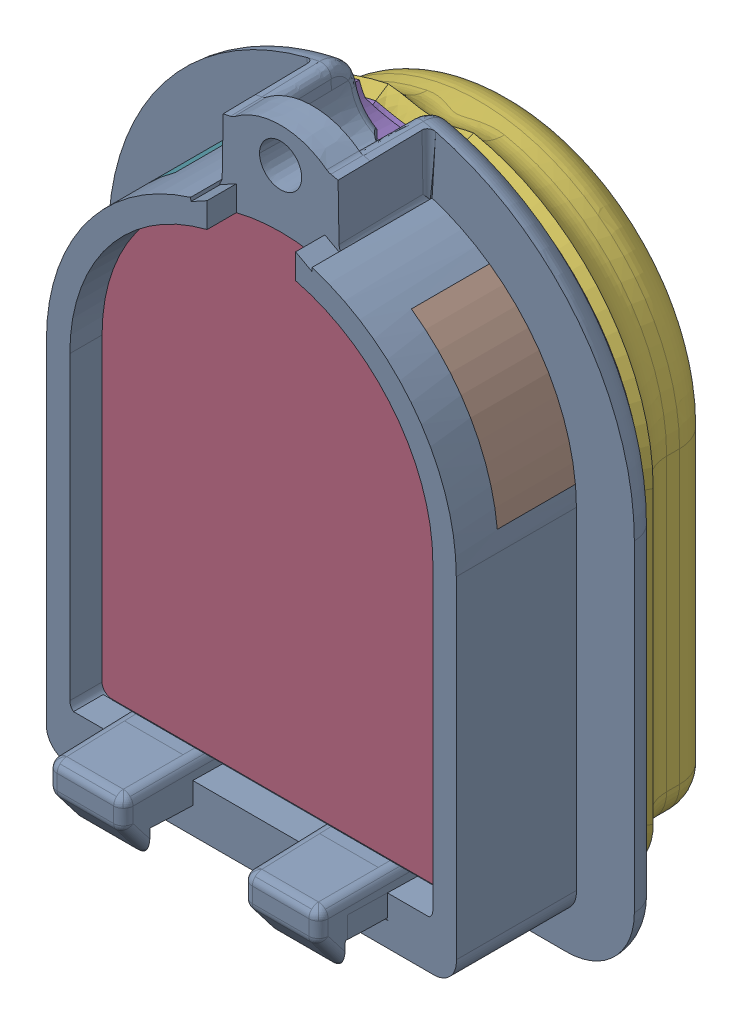
SolidWorks assembly PinDesign_2, configuration 默认. Lengths in mm.
Overall size (26.95 34.26 16.36).
9 component instances, 8 part files, 24 mates.
Components (placement in the parent):
- pin2Tip1-1: pin2Tip1 [默认] at (-1.9035 7.7463 -5.5591) size (26.95 34.26 11.2)
- pin2lensnew-1: pin2lensnew [默认] at (-1.9035 7.7463 -5.5591) size (18.6 25.2 6)
- pin2Skin0.2-1: pin2Skin0.2 [默认] at (-1.9035 7.4963 -5.5591) x (-1 0 0) z (0 0 -1) size (23.9 30.06 5.2)
- pin2Skin1-1: pin2Skin1 [默认] at (-1.9035 7.4963 -5.5591) x (-1 0 0) z (0 0 -1) size (22.77 29.32 5.25) (hidden)
- pin2sidelens1-1: pin2sidelens1 [默认] at (-1.9035 7.7463 -6.2091) size (6.4 7.71 4)
- pin2sidelens1-2: pin2sidelens1 [默认] at (-1.9035 7.7463 2.0909) x (-1 0 0) z (0 0 -1) size (6.4 7.71 4)
- pin2bottomlens-1: pin2bottomlens [默认] at (-5.9035 -10.5037 0.4409) x (1 0 0) z (0 1 0) size (8 4.5 2.35)
- pin2PinMarker_2mm-1: pin2PinMarker_2mm [默认] at (5.5965 8.9053 -8.7591) x (0 -1 0) z (0 0 -1) size (22.28 16.28 2)
- pin2MarkerTIp-1: pin2MarkerTIp [默认] at (-1.9035 4.4053 -8.7591) x (0 1 0) z (0 0 1) size (22 16 0.4)
Mates (geometry in assembly coordinates):
- 同心1: concentric aligned: cylinder of Tip1-1 through (-1.9035 7.7463 51.2878) axis (0 0 -1) radius 9.3; cylinder of lensnew-1 through (-1.9035 7.7463 0.4409) axis (0 0 -1) radius 9.3
- 重合1: coincident anti-aligned: plane of Tip1-1 through (-1.9035 -8.1537 51.2878) normal (0 1 0); plane of lensnew-1 through (-11.2035 -8.1537 0.4409) normal (0 -1 0)
- 重合2: coincident aligned: plane of Tip1-1 through (-1.964 4.3089 -5.5591) normal (0 0 -1); plane of lensnew-1 through (-1.9035 7.7463 -5.5591) normal (0 0 -1)
- 重合3: coincident anti-aligned: plane of lensnew-1 through (-1.9035 7.7463 -5.5591) normal (0 0 -1); plane of Skin0.2-1 through (-1.9035 7.4963 -5.5591) normal (0 0 1)
- 同心2: concentric aligned: cone of Tip1-1 through (-1.9035 19.9963 -1.0591) axis (0 0 1); cylinder of Skin0.2-1 through (-1.9035 19.9963 -6.3091) axis (0 0 1) radius 2.75
- 宽度1: width aligned: plane of Skin0.2-1 through (-13.8535 7.4963 -5.5591) normal (-1 0 0); plane of Skin0.2-1 through (10.0465 7.4963 -5.5591) normal (1 0 0); plane of Tip1-1 through (-12.4035 7.7463 2.0909) normal (-1 0 0); plane of Tip1-1 through (8.5965 7.7463 2.0909) normal (1 0 0)
- 重合4: coincident anti-aligned: plane of Skin0.2-1 through (-1.9035 7.4963 -10.7591) normal (0 0 -1); plane of Skin1-1 through (-1.9035 7.4963 -10.7591) normal (0 0 1)
- 宽度2: width anti-aligned: plane of Skin0.2-1 through (-13.8535 7.4963 -5.5591) normal (-1 0 0); plane of Skin0.2-1 through (10.0465 7.4963 -5.5591) normal (1 0 0); plane of Skin1-1 through (-12.8325 0.0508 -6.2245) normal (-0.891007 0 0.45399); plane of Skin1-1 through (9.0255 0.0508 -6.2245) normal (0.891007 0 0.45399)
- 重合5: coincident aligned: cone of Skin0.2-1 through (-1.9035 7.4963 -6.2245) axis (0 0 1); cone of Skin1-1 through (-1.9035 7.4963 -6.2245) axis (0 0 1)
- 重合6: coincident anti-aligned: plane of Tip1-1 through (-16.7251 9.2061 -4.0591) normal (0.104528 0.994522 0); plane of sidelens1-1 through (8.4147 6.5638 -0.0591) normal (-0.104528 -0.994522 0)
- 重合7: coincident anti-aligned: plane of Tip1-1 through (-1.9035 7.7463 -4.0591) normal (0 0 1); plane of sidelens1-1 through (8.4147 6.5638 -4.0591) normal (0 0 -1)
- 同心3: concentric aligned: cylinder of Tip1-1 through (-1.9035 7.7463 2.0909) axis (0 0 -1) radius 10.5; cylinder of sidelens1-1 through (-1.9035 7.7463 -0.0591) axis (0 0 -1) radius 10.5
- 同心4: concentric anti-aligned: cylinder of Tip1-1 through (-1.9035 7.7463 2.0909) axis (0 0 -1) radius 10.5; cylinder of sidelens1-2 through (-1.9035 7.7463 -4.0591) axis (0 0 1) radius 10.5
- 重合8: coincident anti-aligned: plane of Tip1-1 through (12.0819 17.1622 -0.0591) normal (0.104528 -0.994522 0); plane of sidelens1-2 through (-13.0579 14.5199 -4.0591) normal (-0.104528 0.994522 0)
- 重合9: coincident anti-aligned: plane of Tip1-1 through (-1.9035 7.7463 -4.0591) normal (0 0 1); plane of sidelens1-2 through (-1.9035 7.7463 -4.0591) normal (0 0 -1)
- 重合10: coincident anti-aligned: plane of lensnew-1 through (-11.2035 -8.1537 0.4409) normal (0 -1 0); plane of bottomlens-1 through (-5.9035 -8.1537 0.4409) normal (0 1 0)
- 重合11: coincident anti-aligned: plane of Tip1-1 through (-5.9035 -18.1537 0.4409) normal (0 0 -1); plane of bottomlens-1 through (-5.9035 -8.1537 0.4409) normal (0 0 1)
- 重合12: coincident anti-aligned: plane of Tip1-1 through (2.0965 -18.1537 0.4409) normal (-1 0 0); plane of bottomlens-1 through (2.0965 -8.1537 0.4409) normal (1 0 0)
- 对称1: symmetric aligned: plane of Tip1-1 through (8.5965 7.7463 2.0909) normal (1 0 0); plane of Tip1-1 through (-12.4035 7.7463 2.0909) normal (-1 0 0); plane of PinMarker_2mm-1 through (-1.9035 8.9053 -8.7591) normal (-1 0 0)
- 距离1: distance = 10 mm aligned: plane of Skin0.2-1 through (7.3875 -8.5947 -5.5591) normal (0 -1 0); plane of PinMarker_2mm-1 through (5.5965 1.4053 -8.7591) normal (0 -1 0)
- 同心5: concentric anti-aligned: cone of PinMarker_2mm-1 through (-0.4035 14.9053 -8.7591) axis (0 0 1); cylinder of MarkerTIp-1 through (-0.4035 14.9053 -8.3591) axis (0 0 -1) radius 0.5
- 同心6: concentric anti-aligned: cone of PinMarker_2mm-1 through (-3.4035 14.9053 -8.7591) axis (0 0 1); cylinder of MarkerTIp-1 through (-3.4035 14.9053 -8.3591) axis (0 0 -1) radius 0.5
- 重合14: coincident anti-aligned: plane of PinMarker_2mm-1 through (-0.4035 14.9053 -8.7591) normal (0 0 1); plane of MarkerTIp-1 through (-1.9035 4.4053 -8.7591) normal (0 0 -1)
- 重合16: coincident aligned: plane of Skin0.2-1 through (-1.9035 7.4963 -10.7591) normal (0 0 -1); plane of PinMarker_2mm-1 through (-0.4035 5.9053 -10.7591) normal (0 0 -1)
